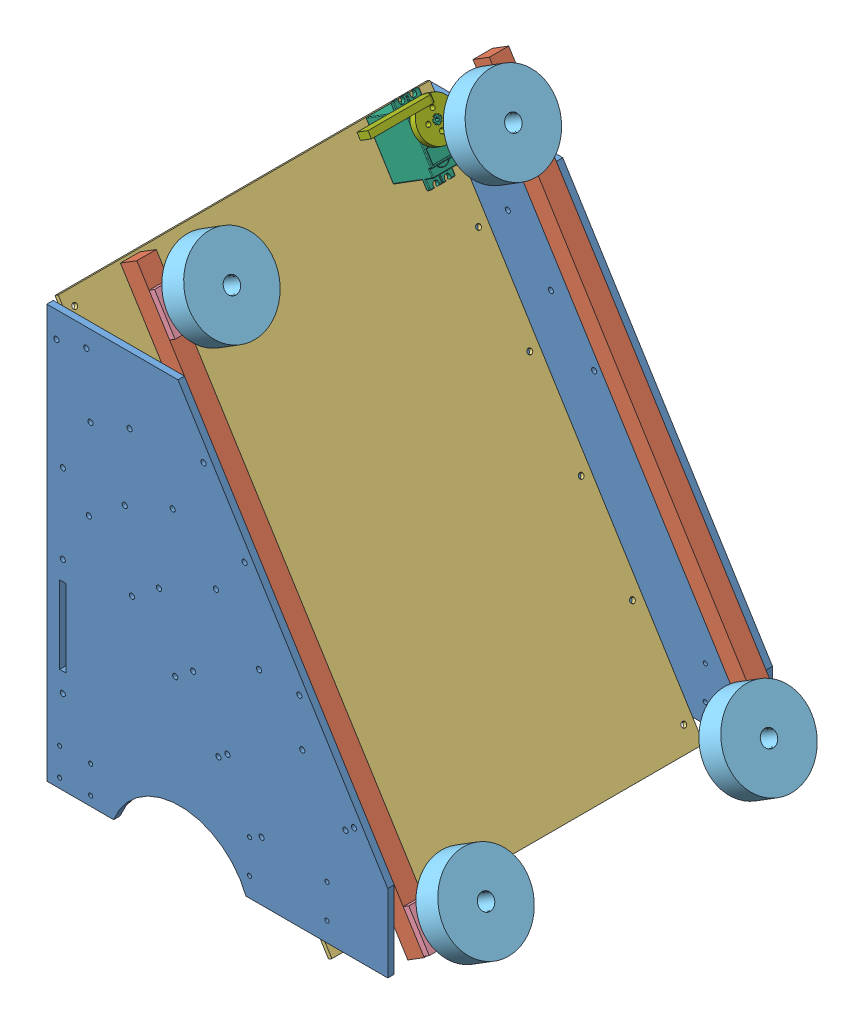
SolidWorks assembly 00A_Assem_Box_Picking, configuration Default. Lengths in mm.
Overall size (324.68 407.67 304.16).
15 component instances, 7 part files, 34 mates.
Components (placement in the parent):
- 004_Box_Holder-1: 004_Box_Holder [Default] at (-191.2969 28.2893 372.9566) size (264.09 320 5)
- 004_Box_Holder-2: 004_Box_Holder [Default] at (-191.2969 28.2893 79.9566) size (264.09 320 5)
- ALU_15x15_420mm-3: ALU_15x15_420mm [Default] at (89.6845 47.1121 365.4566) x (0.848048 0.529919 0) z (0 0 1) size (15 420 15)
- ALU_15x15_420mm-4: ALU_15x15_420mm [Default] at (89.6845 47.1121 92.4566) x (0.848048 0.529919 0) z (0 0 1) size (15 420 15)
- 004_Box_Holder_2-4: 004_Box_Holder_2 [Default] at (-84.0102 182.6072 228.9566) x (0.529919 -0.848048 0) z (0 0 1) size (400 3 288)
- Pulley_Holder-1: Pulley_Holder [Default] at (-109.1299 379.4348 347.9566) x (0.529919 -0.848048 0) z (0 0 1) size (30 5 50)
- Pickup_box_Pulley-1: Pickup_box_Pulley [Default] at (-104.8897 382.0844 337.9566) x (0.529919 -0.848048 0) z (0 0 1) size (66 20 66)
- Pulley_Holder-4: Pulley_Holder [Default] at (87.724 64.4026 347.9566) x (0.529919 -0.848048 0) z (0 0 1) size (30 5 50)
- Pickup_box_Pulley-3: Pickup_box_Pulley [Default] at (91.9643 67.0522 337.9566) x (0.425712 -0.681281 0.595505) z (-0.315569 0.505017 0.803352) size (66 20 66)
- Pulley_Holder-6: Pulley_Holder [Default] at (-109.1299 379.4348 109.9566) x (-0.529919 0.848048 0) z (0 0 -1) size (30 5 50)
- Pulley_Holder-8: Pulley_Holder [Default] at (87.724 64.4026 108.8184) x (-0.529919 0.848048 0) z (0 0 -1) size (30 5 50)
- Pickup_box_Pulley-4: Pickup_box_Pulley [Default] at (-104.8897 382.0844 119.9566) x (0.529919 -0.848048 0) z (0 0 1) size (66 20 66)
- Pickup_box_Pulley-6: Pickup_box_Pulley [Default] at (91.9643 67.0522 118.8184) x (0.529919 -0.848048 0) z (0 0 1) size (66 20 66)
- Servo MG996R.step-1: Servo MG996R.step [Default] at (-187.4499 353.8066 134.9566) x (0.529919 -0.848048 0) z (0 0 1) size (53.62 47.6 20.01)
- tay_chan-1: tay_chan [Default] at (-146.0239 367.9007 124.9566) x (0 0 1) z (-0.529919 0.848048 0) size (65.1 10 30.21)
Mates (geometry in assembly coordinates):
- Coincident2: coincident: plane of assembly; plane of assembly; plane of 004_Box_Holder-1 through (190.0642 28.2893 377.9566) normal (0 -1 0); plane of 004_Box_Holder-2 through (190.0642 28.2893 84.9566) normal (0 -1 0)
- Coincident3: coincident: line of assembly; plane of assembly; line of 004_Box_Holder-1 through (-191.2969 348.2893 372.9566) axis (0 -1 0); plane of 004_Box_Holder-2 through (-191.2969 28.2893 84.9566) normal (-1 0 0)
- Distance2: distance = 298 mm: plane of assembly; plane of assembly; plane of 004_Box_Holder-1 through (-191.2969 28.2893 377.9566) normal (0 0 1); plane of 004_Box_Holder-2 through (-191.2969 28.2893 79.9566) normal (0 0 -1)
- Coincident7: coincident: plane of assembly; plane of assembly; plane of 004_Box_Holder-1 through (-191.2969 28.2893 372.9566) normal (0 0 -1); plane of ALU_15x15_420mm-3 through (-126.5212 407.2667 372.9566) normal (0 0 1)
- Distance4: distance = 7.5 mm: cylinder of assembly; plane of assembly; cylinder of 004_Box_Holder-1 through (46.6757 115.9406 372.9566) axis (0 0 1) radius 2; plane of ALU_15x15_420mm-3 through (-126.5212 407.2667 357.9566) normal (0.848048 0.529919 0)
- Angle1: planar angle = 1.012291 rad: plane of assembly; plane of assembly; plane of ALU_15x15_420mm-3 through (-139.2419 399.3179 357.9566) normal (-0.848048 -0.529919 0); plane of 004_Box_Holder-1 through (190.0642 28.2893 377.9566) normal (0 -1 0)
- Coincident9: coincident: plane of assembly; plane of assembly; plane of ALU_15x15_420mm-3 through (-126.5212 407.2667 357.9566) normal (0.848048 0.529919 0); plane of ALU_15x15_420mm-4 through (-126.5212 407.2667 84.9566) normal (0.848048 0.529919 0)
- Coincident10: coincident: plane of assembly; plane of assembly; plane of 004_Box_Holder-2 through (-191.2969 28.2893 84.9566) normal (0 0 1); plane of ALU_15x15_420mm-4 through (-126.5212 407.2667 84.9566) normal (0 0 -1)
- Coincident11: coincident: plane of assembly; plane of assembly; plane of ALU_15x15_420mm-3 through (89.6845 47.1121 365.4566) normal (0.529919 -0.848048 0); plane of ALU_15x15_420mm-4 through (89.6845 47.1121 92.4566) normal (0.529919 -0.848048 0)
- Distance6: distance = 65 mm: plane of assembly; plane of assembly; plane of ALU_15x15_420mm-4 through (-139.2419 399.3179 84.9566) normal (-0.848048 -0.529919 0); plane of 004_Box_Holder_2-4 through (-81.466 184.197 228.9566) normal (0.848048 0.529919 0)
- Coincident44: coincident: plane of assembly; plane of assembly; plane of 004_Box_Holder-1 through (-191.2969 28.2893 372.9566) normal (0 0 -1); plane of 004_Box_Holder_2-4 through (24.5178 14.5874 372.9566) normal (0 0 1)
- Coincident45: coincident: plane of assembly; plane of assembly; plane of ALU_15x15_420mm-3 through (-126.5212 407.2667 357.9566) normal (0.848048 0.529919 0); plane of Pulley_Holder-1 through (-109.1299 379.4348 347.9566) normal (-0.848048 -0.529919 0)
- Coincident46: coincident: plane of assembly; plane of assembly; plane of ALU_15x15_420mm-3 through (-126.5212 407.2667 372.9566) normal (0 0 1); plane of Pulley_Holder-1 through (-96.9409 369.3636 372.9566) normal (0 0 1)
- Concentric1: concentric: cylinder of assembly; cylinder of assembly; cylinder of Pulley_Holder-1 through (-109.1299 379.4348 337.9566) axis (0.848048 0.529919 0) radius 3; cylinder of Pickup_box_Pulley-1 through (-104.8897 382.0844 337.9566) axis (0.848048 0.529919 0) radius 6
- Coincident47: coincident: plane of assembly; plane of assembly; plane of Pulley_Holder-1 through (-104.8897 382.0844 347.9566) normal (0.848048 0.529919 0); plane of Pickup_box_Pulley-1 through (-104.8897 382.0844 337.9566) normal (-0.848048 -0.529919 0)
- Coincident55: coincident: plane of assembly; plane of assembly; plane of ALU_15x15_420mm-3 through (-126.5212 407.2667 357.9566) normal (0.848048 0.529919 0); plane of Pulley_Holder-4 through (87.724 64.4026 347.9566) normal (-0.848048 -0.529919 0)
- Coincident56: coincident: plane of assembly; plane of assembly; plane of ALU_15x15_420mm-3 through (-126.5212 407.2667 372.9566) normal (0 0 1); plane of Pulley_Holder-4 through (99.9131 54.3315 372.9566) normal (0 0 1)
- Coincident57: coincident: plane of assembly; plane of assembly; plane of Pickup_box_Pulley-1 through (-104.8897 382.0844 337.9566) normal (-0.848048 -0.529919 0); plane of Pulley_Holder-4 through (91.9643 67.0522 347.9566) normal (0.848048 0.529919 0)
- Concentric4: concentric: cylinder of assembly; cylinder of assembly; cylinder of Pulley_Holder-4 through (87.724 64.4026 337.9566) axis (0.848048 0.529919 0) radius 3; cylinder of Pickup_box_Pulley-3 through (91.9643 67.0522 337.9566) axis (0.848048 0.529919 0) radius 6
- Coincident63: coincident: plane of assembly; plane of assembly; plane of Pulley_Holder-4 through (91.9643 67.0522 347.9566) normal (0.848048 0.529919 0); plane of Pickup_box_Pulley-3 through (91.9643 67.0522 337.9566) normal (-0.848048 -0.529919 0)
- Coincident64: coincident: plane of assembly; plane of assembly; plane of ALU_15x15_420mm-4 through (-126.5212 407.2667 84.9566) normal (0.848048 0.529919 0); plane of Pulley_Holder-6 through (-109.1299 379.4348 109.9566) normal (-0.848048 -0.529919 0)
- Coincident66: coincident: plane of assembly; plane of assembly; plane of ALU_15x15_420mm-4 through (-126.5212 407.2667 84.9566) normal (0.848048 0.529919 0); plane of Pulley_Holder-8 through (87.724 64.4026 108.8184) normal (-0.848048 -0.529919 0)
- Coincident69: coincident: plane of assembly; plane of assembly; plane of ALU_15x15_420mm-4 through (-126.5212 407.2667 84.9566) normal (0 0 -1); plane of Pulley_Holder-6 through (-112.8384 394.8051 84.9566) normal (0 0 -1)
- Coincident70: coincident: plane of assembly; plane of assembly; plane of Pulley_Holder-1 through (-112.8384 394.8051 372.9566) normal (-0.529919 0.848048 0); plane of Pulley_Holder-6 through (-112.8384 394.8051 84.9566) normal (-0.529919 0.848048 0)
- Coincident72: coincident: plane of assembly; plane of assembly; plane of Pulley_Holder-4 through (84.0155 79.7729 372.9566) normal (-0.529919 0.848048 0); plane of Pulley_Holder-8 through (84.0155 79.7729 83.8184) normal (-0.529919 0.848048 0)
- Coincident73: coincident: plane of assembly; plane of assembly; plane of Pulley_Holder-6 through (-104.8897 382.0844 109.9566) normal (0.848048 0.529919 0); plane of Pickup_box_Pulley-4 through (-104.8897 382.0844 119.9566) normal (-0.848048 -0.529919 0)
- Concentric5: concentric: cylinder of assembly; cylinder of assembly; cylinder of Pulley_Holder-6 through (-109.1299 379.4348 119.9566) axis (0.848048 0.529919 0) radius 3; cylinder of Pickup_box_Pulley-4 through (-104.8897 382.0844 119.9566) axis (0.848048 0.529919 0) radius 6
- Coincident75: coincident: plane of assembly; plane of assembly; plane of Pulley_Holder-8 through (91.9643 67.0522 108.8184) normal (0.848048 0.529919 0); plane of Pickup_box_Pulley-6 through (91.9643 67.0522 118.8184) normal (-0.848048 -0.529919 0)
- Concentric7: concentric: cylinder of assembly; cylinder of assembly; cylinder of Pulley_Holder-8 through (87.724 64.4026 118.8184) axis (0.848048 0.529919 0) radius 3; cylinder of Pickup_box_Pulley-6 through (91.9643 67.0522 118.8184) axis (0.848048 0.529919 0) radius 6
- Coincident76: coincident: plane of assembly; plane of assembly; plane of 004_Box_Holder_2-4 through (-81.466 184.197 228.9566) normal (0.848048 0.529919 0); plane of Servo MG996R.step-1 through (-187.4499 353.8066 114.9566) normal (-0.848048 -0.529919 0)
- Distance7: distance = 30 mm: plane of assembly; plane of assembly; plane of Servo MG996R.step-1 through (-156.4113 373.2016 114.9566) normal (0 0 -1); plane of 004_Box_Holder-2 through (-191.2969 28.2893 84.9566) normal (0 0 1)
- Coincident78: coincident: line of assembly; plane of assembly; line of 004_Box_Holder_2-4 through (-189.994 352.2168 84.9566) axis (0 0 1); plane of Servo MG996R.step-1 through (-156.4113 373.2016 134.9566) normal (-0.529919 0.848048 0)
- Concentric8: concentric: cylinder of assembly; cylinder of assembly; cylinder of Servo MG996R.step-1 through (-148.4832 366.3639 124.9566) axis (-0.848048 -0.529919 0) radius 6; cylinder of tay_chan-1 through (-141.7836 370.5503 124.9566) axis (-0.848048 -0.529919 0) radius 2.5173
- Coincident79: coincident: plane of assembly; circle of assembly; plane of Servo MG996R.step-1 through (-141.7836 370.5503 124.9566) normal (0.848048 0.529919 0); circle of tay_chan-1
